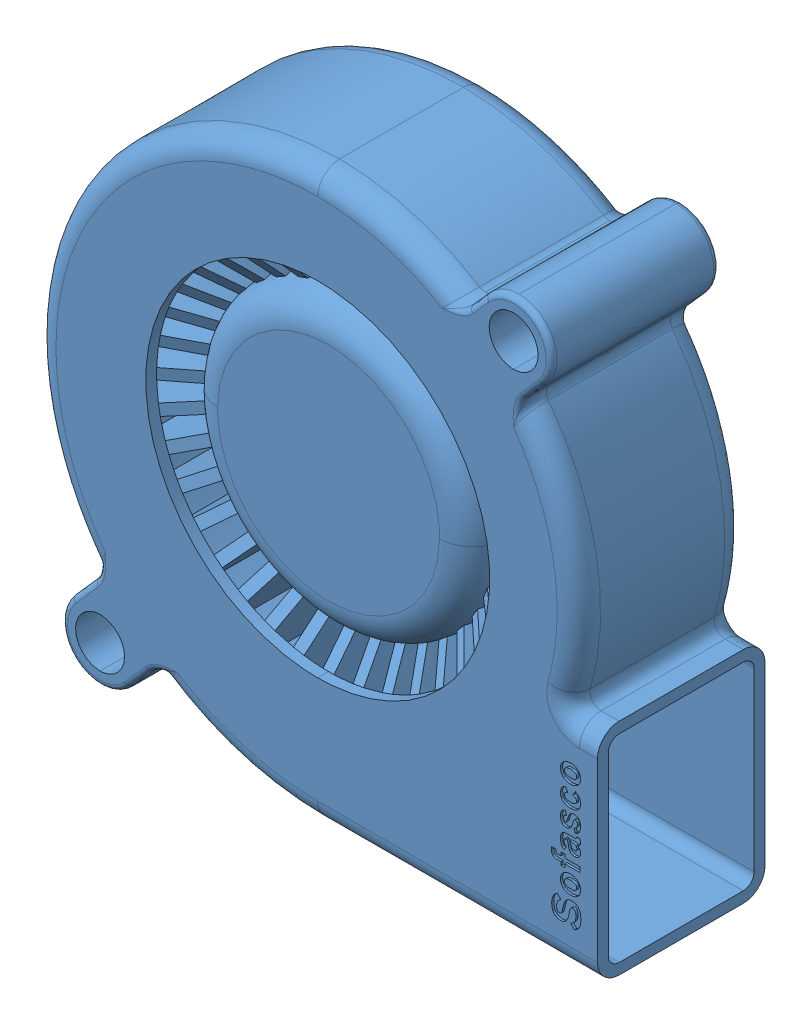
SolidWorks assembly Assem199988, configuration Default. Lengths in mm.
Overall size (74.82 54.09 18.58).
4 component instances, 3 part files, 0 mates.
Components (placement in the parent):
- Assem199988.IGS-1: Assem199988.IGS [Default] at origin size (95.14 55.19 22.38)
  - 5015 12V Blower Fan.IGS-1: 5015 12V Blower Fan.IGS [Default] at (8.4532 33.2278 50.5371) x (1 0 0) z (0 1 0) size (74.82 18.58 54.09)
  - cooling part.IGS-1: cooling part.IGS [Default] at (35.4822 15.7278 42.8371) x (0 0 -1) z (1 0 0) size (17.61 22.41 72.26) (hidden)
  - pan cross head_am_B18.6.7M - M3 x 0.5 x 20 Type I Cross Recessed PHMS --20N.IGS-1: pan cross head_am_B18.6.7M - M3 x 0.5 x 20 Type I Cross Recessed PHMS --20N.IGS [Default] at (-11.5468 10.2278 54.0371) x (0 0 -1) z (1 0 0) size (22.38 5.61 5.61) (hidden)
